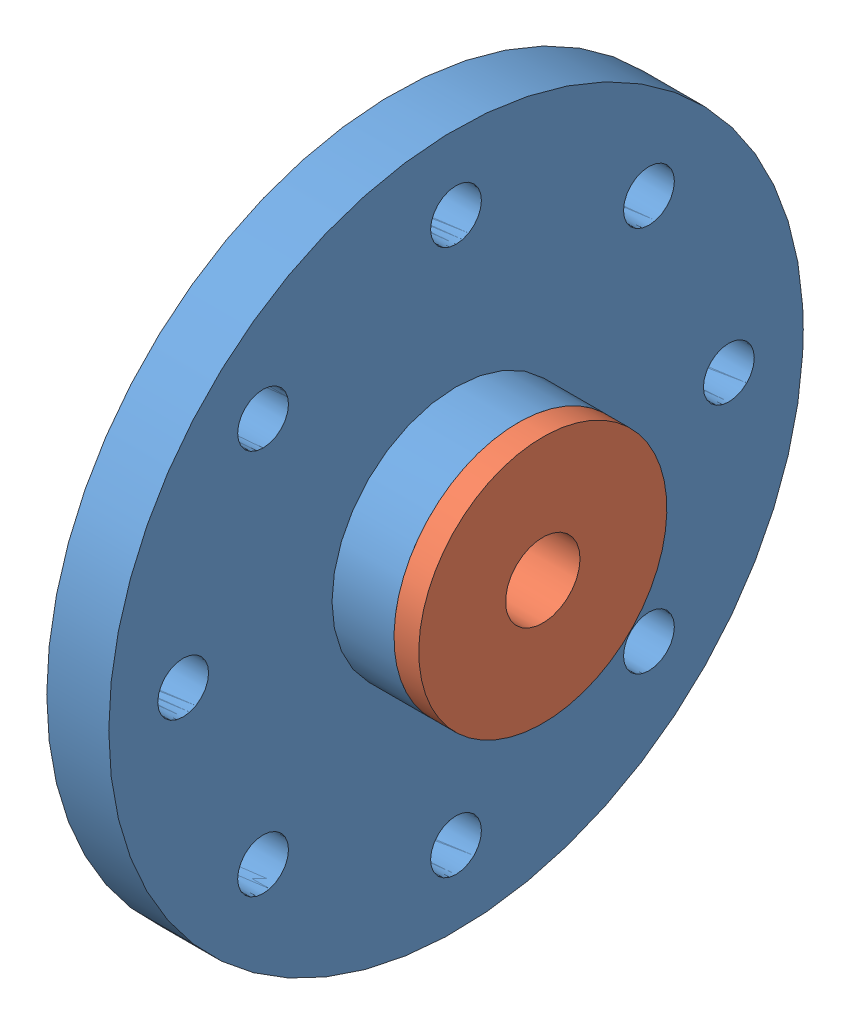
SolidWorks assembly As_back_horn_64_001, configuration Default. Lengths in mm.
Overall size (6 28 28).
3 component instances, 3 part files, 4 mates.
Components (placement in the parent):
- back_horn_64_001-1: back_horn_64_001 [Default] at origin size (5 28 28)
- bearing_2.5_8_3_flange-1: bearing_2.5_8_3_flange [Default] at (5 0 0) x (0 -0.978188 -0.207723) z (0 -0.207723 0.978188) size (10 4 10)
- spring_washer_3mm_001-1: spring_washer_3mm_001 [Default] at (2 0 0) x (0 1 0) z (0 0 1) size (5.5 1 5.5)
Mates (geometry in assembly coordinates):
- Concentric1: concentric anti-aligned: cylinder of back_horn_64_001-1 through (2.5 0 0) axis (-1 0 0) radius 4.1; cylinder of bearing_2.5_8_3_flange-1 through (2 0 0) axis (1 0 0) radius 4
- Coincident3: coincident anti-aligned: plane of back_horn_64_001-1 through (5 0 0) normal (1 0 0); plane of bearing_2.5_8_3_flange-1 through (5 0 0) normal (-1 0 0)
- Coincident4: coincident anti-aligned: circle of bearing_2.5_8_3_flange-1; cylinder of spring_washer_3mm_001-1 through (1 0 0) axis (1 0 0) radius 1.5
- Coincident5: coincident anti-aligned: plane of bearing_2.5_8_3_flange-1 through (2 0 0) normal (-1 0 0); plane of spring_washer_3mm_001-1 through (2 0 0) normal (1 0 0)
